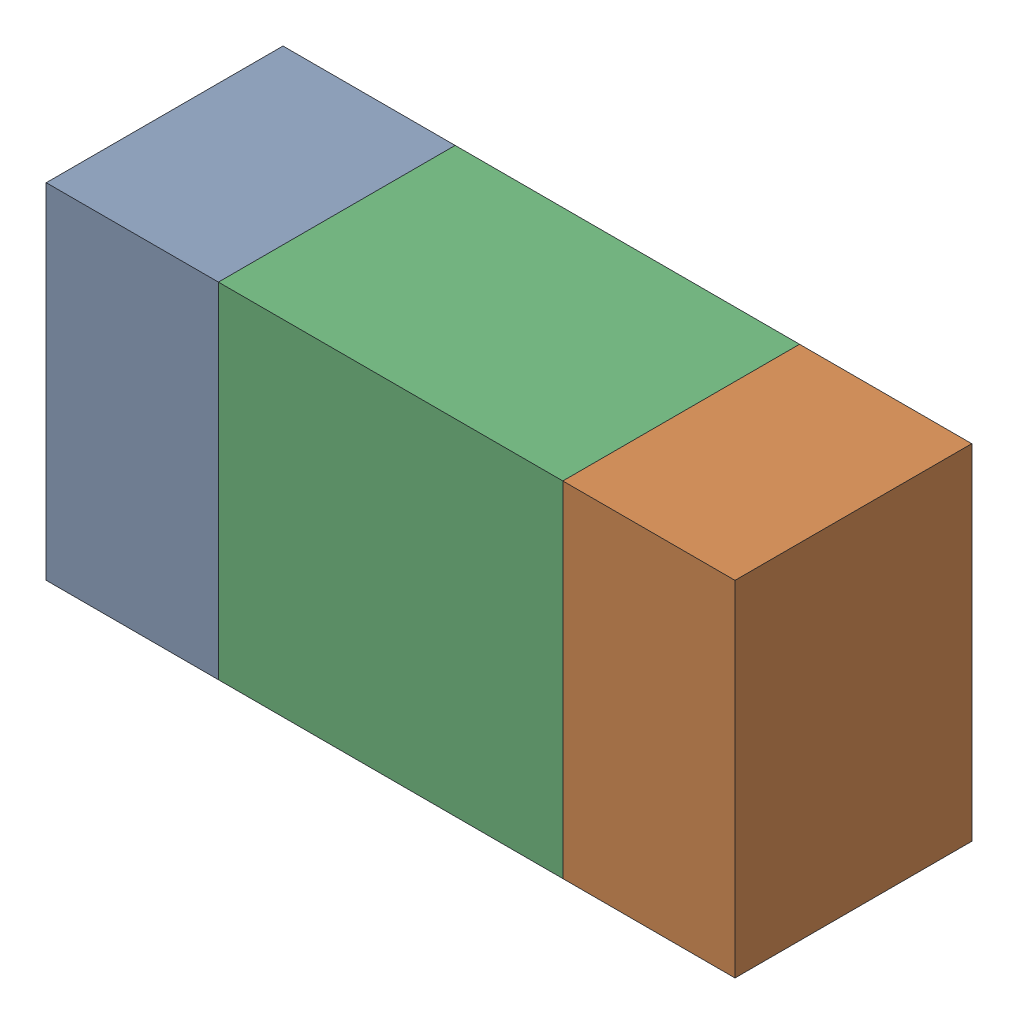
SolidWorks assembly R10, configuration ﾃﾞﾌｫﾙﾄ. Lengths in mm.
Overall size (1.6 0.8 0.55).
6 component instances, 2 part files, 0 mates.
Components (placement in the parent):
- 689261512-1: 689261512 [ﾃﾞﾌｫﾙﾄ] at (6.4001 29.5001 0) size (0.4 0.8 0.55)
  - Extruded_32-1: Extruded_32 [ﾃﾞﾌｫﾙﾄ] at origin size (0.4 0.8 0.55)
- 689261512-2: 689261512 [ﾃﾞﾌｫﾙﾄ] at (7.6001 29.5001 0) size (0.4 0.8 0.55)
  - Extruded_32-1: Extruded_32 [ﾃﾞﾌｫﾙﾄ] at origin size (0.4 0.8 0.55)
- 689261648-1: 689261648 [ﾃﾞﾌｫﾙﾄ] at (7 29.5001 0) size (0.8 0.8 0.55)
  - Extruded_33-1: Extruded_33 [ﾃﾞﾌｫﾙﾄ] at origin size (0.8 0.8 0.55)
